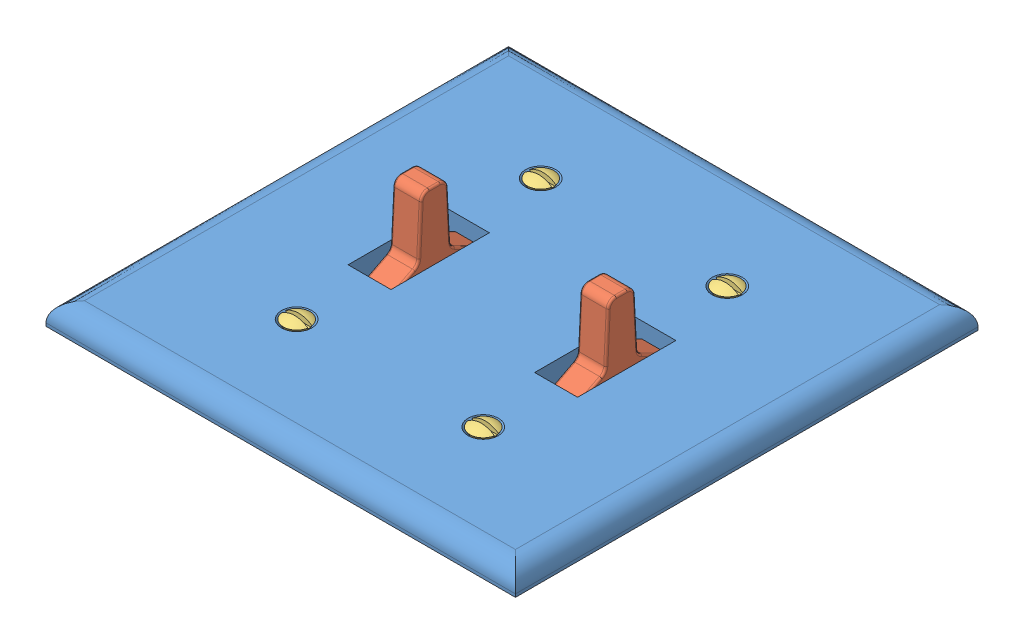
SolidWorks assembly post-switch, configuration Default. Lengths in mm.
Overall size (116 27.59 114.3).
7 component instances, 3 part files, 13 mates.
Components (placement in the parent):
- switchplate-1: switchplate [Default] at (-25.7009 60.0885 119.6547) size (116 5.5 114.3)
- post-1: post [Default] at (-2.1755 67.6218 145.4487) x (0 0 1) z (0 -1 0) size (28.54 7 25.26)
- post-2: post [Default] at (-55.2755 67.6218 104.4945) x (0 0 -1) z (0 -1 0) size (28.54 7 25.26)
- screw-1: screw [Default] at (-5.6755 56.6846 155.8169) x (0 -1 0) z (0 0 1) size (13.64 6.52 6.6)
- screw-2: screw [Default] at (-51.7755 56.6846 155.8169) x (0 -1 0) z (0 0 1) size (13.64 6.52 6.6)
- screw-3: screw [Default] at (-5.6755 56.6846 95.5169) x (0 -1 0) z (0 0 1) size (13.64 6.52 6.6)
- screw-4: screw [Default] at (-51.7755 56.6846 95.5169) x (0 -1 0) z (0 0 1) size (13.64 6.52 6.6)
Mates (geometry in assembly coordinates):
- Distance1: distance = 15 mm aligned: plane of Switch Post-2 through (-48.2755 80.5885 104.4945) normal (0 1 0); plane of Double Switchplate-1 through (-25.7009 65.5885 119.6547) normal (0 1 0)
- Distance2: distance = 1.8 mm anti-aligned: plane of Double Switchplate-1 through (-46.4755 65.5885 113.3318) normal (-1 0 0); plane of Switch Post-2 through (-48.2755 67.6218 104.4945) normal (1 0 0)
- Distance3: distance = 1.8 mm anti-aligned: plane of Switch Post-1 through (-9.1755 67.6218 145.4487) normal (-1 0 0); plane of Double Switchplate-1 through (-10.9755 65.5885 119.6547) normal (1 0 0)
- Distance4: distance = 15 mm aligned: plane of Switch Post-1 through (-9.1755 80.5885 145.4487) normal (0 1 0); plane of Double Switchplate-1 through (-25.7009 65.5885 119.6547) normal (0 1 0)
- Concentric1: concentric aligned: cylinder of Double Switchplate-1 through (-51.7755 65.5885 155.6318) axis (0 -1 0) radius 2.25; cone of Screw-2 through (-13.5774 63.006 155.9613) axis (0 -1 0)
- Coincident5: coincident anti-aligned: plane of Double Switchplate-1 through (-25.7009 65.5885 119.6547) normal (0 1 0); circle of Screw-2
- Concentric2: concentric aligned: cylinder of Double Switchplate-1 through (-5.6755 65.5885 155.6318) axis (0 -1 0) radius 2.25; cone of Screw-1 through (-5.6755 63.0885 155.6318) axis (0 -1 0)
- Concentric3: concentric aligned: cylinder of Double Switchplate-1 through (-51.7755 65.5885 95.3318) axis (0 -1 0) radius 2.25; cone of Screw-4 through (-51.7755 63.0885 95.3318) axis (0 -1 0)
- Concentric4: concentric aligned: cylinder of Double Switchplate-1 through (-5.6755 65.5885 95.3318) axis (0 -1 0) radius 2.25; cone of Screw-3 through (-5.6755 63.0885 95.3318) axis (0 -1 0)
- Coincident6: coincident anti-aligned: plane of Double Switchplate-1 through (-25.7009 65.5885 119.6547) normal (0 1 0); circle of Screw-3
- Coincident7: coincident anti-aligned: plane of Double Switchplate-1 through (-25.7009 65.5885 119.6547) normal (0 1 0); circle of Screw-1
- Coincident8: coincident anti-aligned: plane of Double Switchplate-1 through (-25.7009 65.5885 119.6547) normal (0 1 0); circle of Screw-4
- Coincident9: coincident aligned: plane of screw-1 through (-8.9755 65.1623 155.1318) normal (0 0 1); plane of screw-2 through (-55.0755 65.1623 155.1318) normal (0 0 1)
